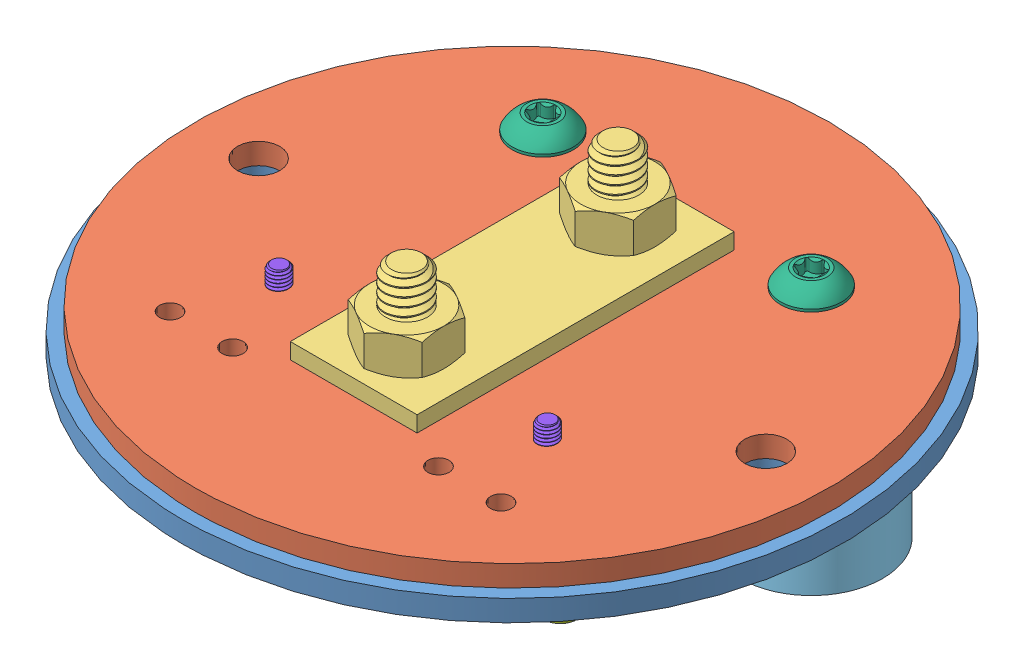
SolidWorks assembly avbay_fore_bulkhead, configuration Default. Lengths in mm.
Overall size (99.06 51.22 99.06).
13 component instances, 8 part files, 31 mates.
Components (placement in the parent):
- bulkplate-1: bulkplate [Default] at (28.2644 47.5506 82.3713) size (99.06 3.17 99.06)
- bulkplate_insert-1: bulkplate_insert [Default] at (28.2644 50.7256 82.3713) size (95.25 3.17 95.25)
- u_bolt_fore-1: u_bolt_fore [2936T68] at (28.2644 35.7767 82.3713) x (0 0 1) z (-1 0 0) size (47.62 51.22 19.05)
- nut-1: nut [95462A029] at (28.2644 44.7725 98.2463) x (1 0 0) z (0 -1 0) size (11.11 12.83 6.51)
- nut-2: nut [95462A029] at (28.2644 44.7725 66.4963) x (1 0 0) z (0 1 0) size (11.11 12.83 6.51)
- charge_cap-1: charge_cap [4880K842] at (48.4256 34.4538 57.6063) x (1 0 0) z (0 -1 0) size (24.13 24.13 26.19)
- charge_cap-2: charge_cap [4880K842] at (8.1031 34.4538 57.6063) x (1 0 0) z (0 -1 0) size (24.13 24.13 26.19)
- 10_32_screw-1: 10_32_screw [90600A124] at (48.4256 56.466 57.6063) x (1 0 0) z (0 1 0) size (9.17 9.17 15.64)
- 10_32_screw-2: 10_32_screw [90600A124] at (8.1031 56.466 57.6063) x (1 0 0) z (0 1 0) size (9.17 9.17 15.64)
- terminal_block_2-1: terminal_block_2 [Default] at (3.4041 47.5506 97.2303) x (-1 0 0) z (0 0 1) size (18.8 12.06 17.02)
- m3_16_screw-1: m3_16_screw [92095A184] at (8.1031 38.9156 97.2303) x (1 0 0) z (0 -1 0) size (5.7 5.7 18)
- terminal_block_2-2: terminal_block_2 [Default] at (53.1246 47.5506 97.2303) x (1 0 0) z (0 0 -1) size (18.8 12.06 17.02)
- m3_16_screw-2: m3_16_screw [92095A184] at (48.4256 38.9156 97.2303) x (1 0 0) z (0 -1 0) size (5.7 5.7 18)
Mates (geometry in assembly coordinates):
- Concentric1: concentric aligned: cylinder of bulkplate-1 through (28.2644 50.7256 82.3713) axis (0 -1 0) radius 49.53; cylinder of bulkplate_insert-1 through (28.2644 53.9006 82.3713) axis (0 -1 0) radius 47.625
- Coincident2: coincident anti-aligned: plane of bulkplate-1 through (28.2644 50.7256 82.3713) normal (0 1 0); plane of bulkplate_insert-1 through (28.2644 50.7256 82.3713) normal (0 -1 0)
- Coincident3: coincident anti-aligned: plane of bulkplate_insert-1 through (28.2644 53.9006 82.3713) normal (0 1 0); plane of u_bolt_fore-1 through (37.7894 53.9006 58.5588) normal (0 -1 0)
- Coincident4: coincident anti-aligned: plane of bulkplate-1 through (28.2644 47.5506 82.3713) normal (1 0 0); plane of u_bolt_fore-1 through (28.2644 35.7767 82.3713) normal (-1 0 0)
- Coincident5: coincident aligned: plane of bulkplate-1 through (28.2644 47.5506 82.3713) normal (0 0 1); plane of u_bolt_fore-1 through (28.2644 35.7767 82.3713) normal (0 0 1)
- Concentric2: concentric aligned: cylinder of u_bolt_fore-1 through (28.2644 42.1267 66.4963) axis (0 1 0) radius 3.175; cone of nut-2 through (28.2644 42.3119 66.4963) axis (0 1 0)
- Coincident6: coincident anti-aligned: plane of bulkplate-1 through (28.2644 47.5506 82.3713) normal (0 -1 0); plane of nut-2 through (22.7081 47.5506 63.2884) normal (0 1 0)
- Concentric3: concentric anti-aligned: cylinder of u_bolt_fore-1 through (28.2644 35.7767 98.2463) axis (0 1 0) radius 3.175; circle of nut-1
- Coincident8: coincident anti-aligned: plane of bulkplate-1 through (28.2644 47.5506 82.3713) normal (0 -1 0); plane of nut-1 through (22.7081 47.5506 101.4542) normal (0 1 0)
- Coincident9: coincident anti-aligned: plane of bulkplate-1 through (28.2644 47.5506 82.3713) normal (0 -1 0); plane of charge_cap-2 through (8.1031 47.5506 57.6063) normal (0 1 0)
- Coincident10: coincident anti-aligned: plane of bulkplate-1 through (28.2644 47.5506 82.3713) normal (0 -1 0); plane of charge_cap-1 through (48.4256 47.5506 57.6063) normal (0 1 0)
- Tangent1: tangent aligned: cylinder of u_bolt_fore-1 through (28.2644 42.1267 66.4963) axis (0 1 0) radius 3.175; plane of charge_cap-2 through (3.1057 40.9149 69.6713) normal (0 0 1)
- Tangent2: tangent aligned: cylinder of u_bolt_fore-1 through (28.2644 42.1267 66.4963) axis (0 1 0) radius 3.175; plane of charge_cap-1 through (43.4282 40.9149 69.6713) normal (0 0 1)
- Coincident11: coincident aligned: plane of charge_cap-1 through (43.4282 40.9149 69.6713) normal (0 0 1); plane of charge_cap-2 through (3.1057 40.9149 69.6713) normal (0 0 1)
- Distance1: distance = 2.54 mm anti-aligned: plane of charge_cap-1 through (36.3606 40.9149 52.6088) normal (-1 0 0); plane of nut-2 through (33.8206 47.5506 69.7042) normal (1 0 0)
- Distance2: distance = 2.54 mm anti-aligned: plane of charge_cap-2 through (20.1681 40.9149 62.6038) normal (1 0 0); plane of nut-2 through (22.7081 47.5506 63.2884) normal (-1 0 0)
- Coincident15: coincident anti-aligned: plane of bulkplate_insert-1 through (28.2644 53.9006 82.3713) normal (0 1 0); plane of 10_32_screw-2 through (8.1031 53.9006 53.0216) normal (0 -1 0)
- Coincident16: coincident anti-aligned: plane of bulkplate_insert-1 through (28.2644 53.9006 82.3713) normal (0 1 0); plane of 10_32_screw-1 through (48.4256 53.9006 53.0216) normal (0 -1 0)
- Concentric5: concentric aligned: cylinder of bulkplate_insert-1 through (48.4256 72.1569 57.6063) axis (0 -1 0) radius 1.9844; circle of 10_32_screw-1
- Concentric6: concentric aligned: cylinder of bulkplate_insert-1 through (8.1031 72.1569 57.6063) axis (0 -1 0) radius 1.9844; circle of 10_32_screw-2
- Coincident19: coincident anti-aligned: plane of bulkplate-1 through (28.2644 47.5506 82.3713) normal (0 -1 0); plane of terminal_block_2-1 through (8.1031 47.5506 97.2303) normal (0 1 0)
- Parallel2: parallel anti-aligned: plane of charge_cap-2 through (3.1057 40.9149 69.6713) normal (0 0 1); plane of terminal_block_2-1 through (0.4831 40.5656 88.7213) normal (0 0 -1)
- Coincident21: coincident: plane of charge_cap-2 through (8.1031 34.4538 57.6063) normal (1 0 0); point of terminal_block_2-1
- Distance3: distance = 19.05 mm anti-aligned: plane of terminal_block_2-1 through (9.8811 40.5656 88.7213) normal (0 0 -1); plane of charge_cap-2 through (3.1057 40.9149 69.6713) normal (0 0 1)
- Coincident23: coincident: plane of charge_cap-1 through (48.4256 34.4538 57.6063) normal (1 0 0); point of terminal_block_2-2
- Coincident24: coincident anti-aligned: plane of bulkplate-1 through (28.2644 47.5506 82.3713) normal (0 -1 0); plane of terminal_block_2-2 through (39.0276 47.5506 97.2303) normal (0 1 0)
- Coincident26: coincident aligned: plane of terminal_block_2-1 through (9.8811 40.5656 88.7213) normal (0 0 -1); plane of terminal_block_2-2 through (46.6476 40.5656 88.7213) normal (0 0 -1)
- Concentric7: concentric anti-aligned: cylinder of terminal_block_2-1 through (8.1031 40.5656 97.2303) axis (0 1 0) radius 1.5875; cylinder of m3_16_screw-1 through (8.1031 38.9156 97.2303) axis (0 -1 0) radius 2.85
- Coincident27: coincident anti-aligned: plane of terminal_block_2-1 through (17.5011 40.5656 97.2303) normal (0 -1 0); plane of m3_16_screw-1 through (10.9531 40.5656 97.2303) normal (0 1 0)
- Coincident28: coincident anti-aligned: plane of terminal_block_2-2 through (39.0276 40.5656 97.2303) normal (0 -1 0); plane of m3_16_screw-2 through (51.2756 40.5656 97.2303) normal (0 1 0)
- Concentric8: concentric anti-aligned: cylinder of terminal_block_2-2 through (48.4256 40.5656 97.2303) axis (0 1 0) radius 1.5875; cylinder of m3_16_screw-2 through (48.4256 38.9156 97.2303) axis (0 -1 0) radius 2.85
